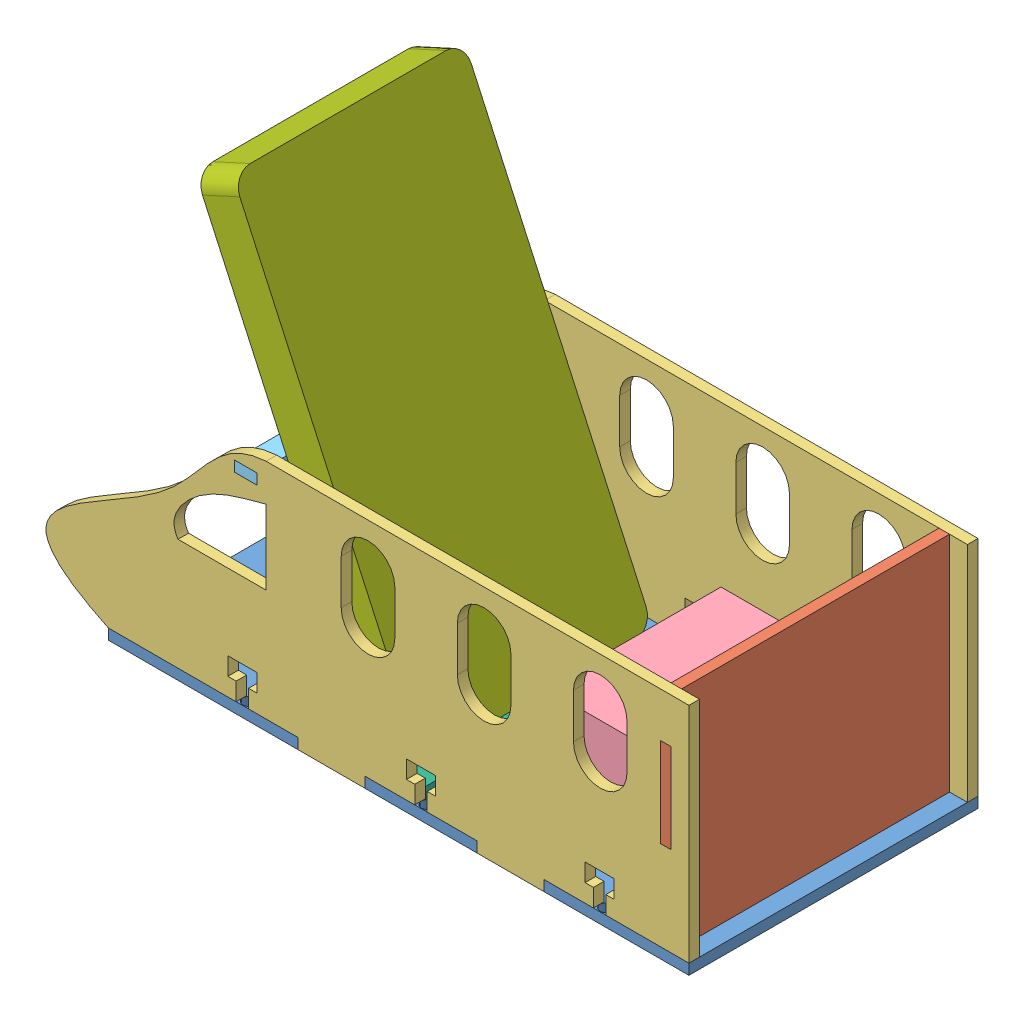
SolidWorks assembly airplane, configuration Default. Lengths in mm.
Overall size (185.75 124.06 82.2).
8 component instances, 7 part files, 24 mates.
Components (placement in the parent):
- plane_btm_short-2: plane_btm_short [Default] at (16.5835 38.9149 162.3178) size (165.1 3 82.2)
- plane_back-3: plane_back [Default] at (59.3035 73.6649 162.3178) size (3 66.5 82.2)
- plane_side_short-3: plane_side_short [Default] at (16.5835 73.6649 200.4178) size (185.75 66.5 3)
- plane_side_short-4: plane_side_short [Default] at (16.5835 73.6649 121.2178) size (185.75 66.5 3)
- pcb-1: pcb [Default] at (34.3035 41.9149 161.2178) x (0 0 -1) z (0 1 0) size (50 50 30)
- stick-1: stick [Default] at (-58.664 99.7178 121.2178) size (6.35 3 82.2)
- stick_short-1: stick_short [Default] at (-13.7568 43.4149 124.2178) size (6.35 3 76.2)
- phone-2: phone [Default] at (-54.5189 99.0937 162.1108) x (0 0 -1) z (0.909633 0.415412 0) size (65.79 129.79 11.68)
Mates (geometry in assembly coordinates):
- Coincident5: coincident anti-aligned: plane of plane_btm_short-2 through (62.3035 41.9149 175.0178) normal (0 0 -1); plane of plane_back-3 through (62.3035 41.9149 175.0178) normal (0 0 1)
- Coincident6: coincident anti-aligned: plane of plane_btm_short-2 through (62.3035 41.9149 149.6178) normal (0 0 1); plane of plane_back-3 through (62.3035 41.9149 149.6178) normal (0 0 -1)
- Coincident7: coincident aligned: plane of plane_btm_short-2 through (16.5835 38.9149 162.3178) normal (0 -1 0); plane of plane_back-3 through (62.3035 38.9149 175.0178) normal (0 -1 0)
- Coincident8: coincident anti-aligned: plane of plane_btm_short-2 through (62.3035 41.9149 175.0178) normal (-1 0 0); plane of plane_back-3 through (62.3035 73.6649 162.3178) normal (1 0 0)
- Coincident9: coincident anti-aligned: plane of plane_back-3 through (62.3035 92.7149 200.4178) normal (0 1 0); plane of plane_side_short-3 through (62.3035 92.7149 203.4178) normal (0 -1 0)
- Coincident10: coincident anti-aligned: plane of plane_back-3 through (62.3035 67.3149 200.4178) normal (0 -1 0); plane of plane_side_short-3 through (62.3035 67.3149 203.4178) normal (0 1 0)
- Coincident11: coincident aligned: plane of plane_back-3 through (62.3035 92.7149 203.4178) normal (0 0 1); plane of plane_side_short-3 through (-96.1703 74.3104 203.4178) normal (0 0 1)
- Coincident12: coincident: plane of plane_btm_short-2 through (67.3835 41.9149 121.2178) normal (1 0 0); plane of plane_side_short-3 through (67.3835 105.4149 203.4178) normal (1 0 0)
- Coincident13: coincident: plane of plane_back-3 through (62.3035 92.7149 124.2178) normal (0 1 0); plane of plane_side_short-4 through (62.3035 92.7149 124.2178) normal (0 -1 0)
- Coincident14: coincident anti-aligned: plane of plane_back-3 through (62.3035 67.3149 124.2178) normal (0 -1 0); plane of plane_side_short-4 through (62.3035 67.3149 124.2178) normal (0 1 0)
- Coincident15: coincident aligned: plane of plane_btm_short-2 through (67.3835 41.9149 121.2178) normal (1 0 0); plane of plane_side_short-4 through (67.3835 105.4149 124.2178) normal (1 0 0)
- Coincident16: coincident aligned: plane of plane_back-3 through (62.3035 92.7149 121.2178) normal (0 0 -1); plane of plane_side_short-4 through (-96.1703 74.3104 121.2178) normal (0 0 -1)
- Coincident17: coincident anti-aligned: plane of plane_btm_short-2 through (16.5835 41.9149 162.3178) normal (0 1 0); plane of pcb-1 through (34.3035 41.9149 161.2178) normal (0 -1 0)
- Coincident18: coincident anti-aligned: plane of plane_back-3 through (59.3035 73.6649 162.3178) normal (-1 0 0); plane of pcb-1 through (59.3035 71.9149 186.2178) normal (1 0 0)
- Distance1: distance = 12 mm anti-aligned: plane of pcb-1 through (59.3035 71.9149 136.2178) normal (0 0 -1); plane of plane_side_short-4 through (-96.1703 74.3104 124.2178) normal (0 0 1)
- Coincident20: coincident aligned: plane of plane_side_short-3 through (-96.1703 74.3104 203.4178) normal (0 0 1); plane of stick-1 through (-58.664 99.7178 203.4178) normal (0 0 1)
- Coincident21: coincident anti-aligned: plane of plane_side_short-3 through (-55.489 101.2178 203.4178) normal (-1 0 0); plane of stick-1 through (-55.489 98.2178 203.4178) normal (1 0 0)
- Coincident22: coincident anti-aligned: plane of plane_side_short-3 through (-61.839 101.2178 203.4178) normal (0 -1 0); plane of stick-1 through (-55.489 101.2178 203.4178) normal (0 1 0)
- Coincident23: coincident anti-aligned: plane of plane_side_short-3 through (-96.1703 74.3104 200.4178) normal (0 0 -1); plane of stick_short-1 through (-13.7568 43.4149 200.4178) normal (0 0 1)
- Coincident24: coincident anti-aligned: plane of plane_btm_short-2 through (16.5835 41.9149 162.3178) normal (0 1 0); plane of stick_short-1 through (-10.5818 41.9149 200.4178) normal (0 -1 0)
- Coincident25: coincident aligned: plane of plane_side_short-4 through (-10.5818 41.9149 124.2178) normal (1 0 0); plane of stick_short-1 through (-10.5818 41.9149 200.4178) normal (1 0 0)
- Coincident26: coincident aligned: line of stick_short-1 through (-16.9318 44.9149 200.4178) axis (0 0 -1); line of phone-2 through (-16.9318 44.9149 189.9238) axis (0 0 -1)
- Coincident27: coincident: line of stick-1 through (-55.489 101.2178 203.4178) axis (0 0 -1); plane of phone-2 through (-54.5189 99.0937 162.1108) normal (-0.909633 -0.415412 0)
- Distance2: distance = 5 mm anti-aligned: plane of phone-2 through (-16.9318 44.9149 129.2178) normal (0 0 -1); plane of plane_side_short-4 through (-96.1703 74.3104 124.2178) normal (0 0 1)
